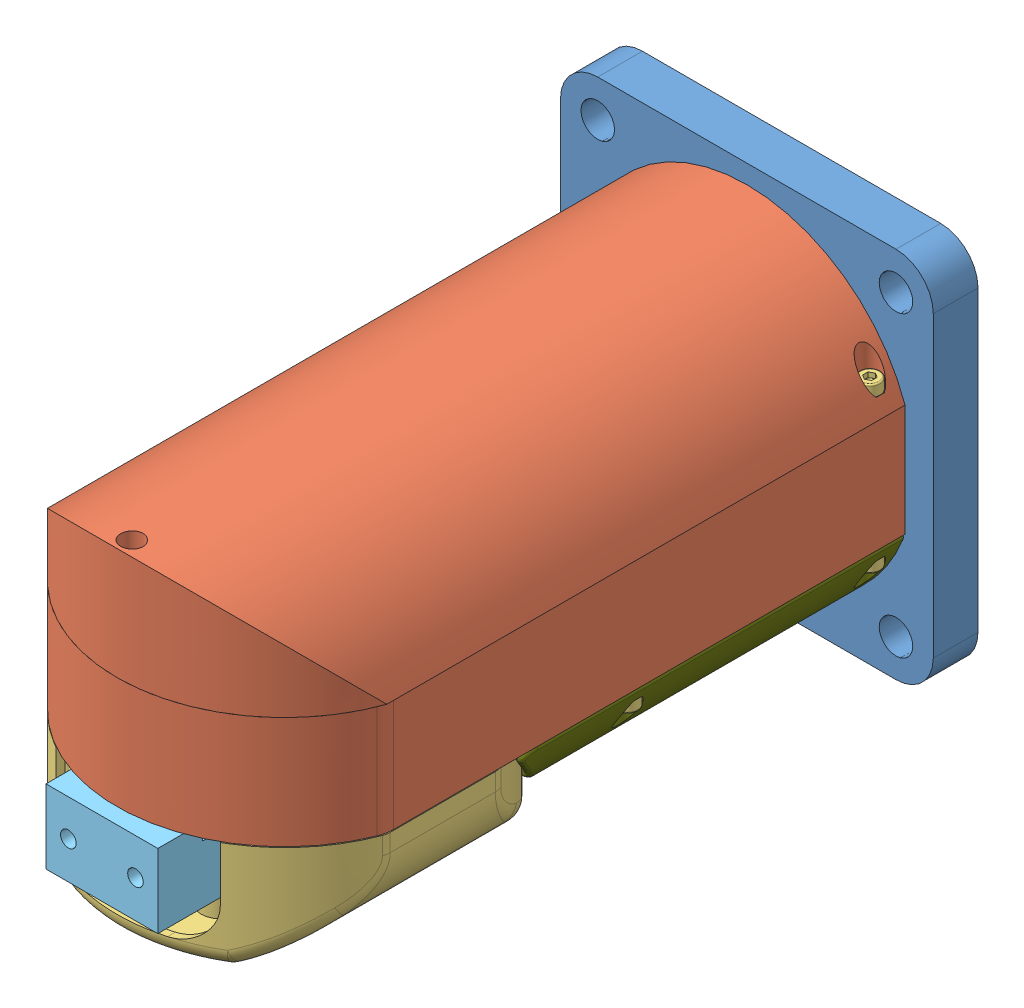
SolidWorks assembly 基座, configuration 默认. Lengths in mm.
Overall size (118.25 100 217.02).
86 component instances, 23 part files, 119 mates.
Components (placement in the parent):
- 90000001-底座安装板-1: 90000001-底座安装板 [默认] at origin size (100 100 12)
- 90000002-底座中间部件-1: 90000002-底座中间部件 [默认] at (0 0 -40) size (118.25 75 217.02)
- hexagon socket head cap screws gb-2: hexagon socket head cap screws gb [GB_FASTENER_SCREWS_HSHCS M6X20-N] at (37.5 0 -11.5) x (0 0 1) z (-1 0 0) size (26 10 10)
- hexagon socket head cap screws gb-3: hexagon socket head cap screws gb [GB_FASTENER_SCREWS_HSHCS M6X20-N] at (-37.5 0 -11.5) x (0 0 1) z (-1 0 0) size (26 10 10)
- 90000013-SHF-17-80-2SH-SP刚柔轮组件-1: 90000013-SHF-17-80-2SH-SP刚柔轮组件 [默认] at (0 7 124) x (0 0 -1) z (0 -1 0) size (80 80 29.5)
- 90000006-J1轴转接法兰-1: 90000006-J1轴转接法兰 [默认] at (0 0 79) x (-1 0 0) z (0 0 1) size (64 19.8 81.67)
- hexagon socket head cap screws gb-4: hexagon socket head cap screws gb [GB_FASTENER_SCREWS_HSHCS M3X25-N] at (18.5 -15 156.0429) x (0 1 0) z (0 0 1) size (28 5.5 5.5)
- hexagon socket head cap screws gb-5: hexagon socket head cap screws gb [GB_FASTENER_SCREWS_HSHCS M3X25-N] at (0 -15 161) x (0 1 0) z (-0.5 0 0.866025) size (28 5.5 5.5)
- hexagon socket head cap screws gb-6: hexagon socket head cap screws gb [GB_FASTENER_SCREWS_HSHCS M3X25-N] at (-18.5 -15 156.0429) x (0 1 0) z (-0.866025 0 0.5) size (28 5.5 5.5)
- hexagon socket head cap screws gb-7: hexagon socket head cap screws gb [GB_FASTENER_SCREWS_HSHCS M3X25-N] at (-32.0429 -15 142.5) x (0 1 0) z (-1 0 0) size (28 5.5 5.5)
- hexagon socket head cap screws gb-8: hexagon socket head cap screws gb [GB_FASTENER_SCREWS_HSHCS M3X25-N] at (-37 -15 124) x (0 1 0) z (-0.866025 0 -0.5) size (28 5.5 5.5)
- hexagon socket head cap screws gb-9: hexagon socket head cap screws gb [GB_FASTENER_SCREWS_HSHCS M3X25-N] at (-32.0429 -15 105.5) x (0 1 0) z (-0.5 0 -0.866025) size (28 5.5 5.5)
- hexagon socket head cap screws gb-10: hexagon socket head cap screws gb [GB_FASTENER_SCREWS_HSHCS M3X25-N] at (-18.5 -15 91.9571) x (0 1 0) z (0 0 -1) size (28 5.5 5.5)
- hexagon socket head cap screws gb-11: hexagon socket head cap screws gb [GB_FASTENER_SCREWS_HSHCS M3X25-N] at (0 -15 87) x (0 1 0) z (0.5 0 -0.866025) size (28 5.5 5.5)
- hexagon socket head cap screws gb-12: hexagon socket head cap screws gb [GB_FASTENER_SCREWS_HSHCS M3X25-N] at (18.5 -15 91.9571) x (0 1 0) z (0.866025 0 -0.5) size (28 5.5 5.5)
- hexagon socket head cap screws gb-13: hexagon socket head cap screws gb [GB_FASTENER_SCREWS_HSHCS M3X25-N] at (32.0429 -15 105.5) x (0 1 0) z (1 0 0) size (28 5.5 5.5)
- hexagon socket head cap screws gb-14: hexagon socket head cap screws gb [GB_FASTENER_SCREWS_HSHCS M3X25-N] at (37 -15 124) x (0 1 0) z (0.866025 0 0.5) size (28 5.5 5.5)
- hexagon socket head cap screws gb-15: hexagon socket head cap screws gb [GB_FASTENER_SCREWS_HSHCS M3X25-N] at (32.0429 -15 142.5) x (0 1 0) z (0.5 0 0.866025) size (28 5.5 5.5)
- 90000013-SHF-17-80-2SH-SP波发生器-1: 90000013-SHF-17-80-2SH-SP波发生器 [默认] at (0 -11.9 124) x (0.178391 0 0.98396) z (0 -1 0) size (45 45 7.6)
- 90000010-J1轴减速机安装法兰-1: 90000010-J1轴减速机安装法兰 [默认] at (0 16 124) x (1 0 0) z (0 -1 0) size (64 64 12.5)
- 90000009-J1轴减速机安装输出轴-1: 90000009-J1轴减速机安装输出轴 [默认] at (0 -30.5 124) x (0.178391 0 0.98396) z (0 1 0) size (27 27 62.5)
- hexagon socket head cap screws gb-16: hexagon socket head cap screws gb [GB_FASTENER_SCREWS_HSHCS M4X8-N] at (-1.9623 -5.9 113.1764) x (0 -1 0) z (0 0 1) size (12 7 7)
- hexagon socket head cap screws gb-17: hexagon socket head cap screws gb [GB_FASTENER_SCREWS_HSHCS M4X8-N] at (1.9623 -5.9 134.8236) x (0 -1 0) z (0 0 1) size (12 7 7)
- 90000012-轴承636-1: 90000012-轴承636 [默认] at (0 -31 124) x (-0.837169 0 -0.546944) z (0 1 0) size (22 22 9)
- hexagon socket head cap screws gb-18: hexagon socket head cap screws gb [GB_FASTENER_SCREWS_HSHCS M3X20-N] at (-15.8702 -30.5 102.1565) x (0 1 0) z (0 0 1) size (23 5.5 5.5)
- hexagon socket head cap screws gb-22: hexagon socket head cap screws gb [GB_FASTENER_SCREWS_HSHCS M3X20-N] at (-21.8435 -30.5 108.1298) x (0 1 0) z (0 0 1) size (23 5.5 5.5)
- hexagon socket head cap screws gb-26: hexagon socket head cap screws gb [GB_FASTENER_SCREWS_HSHCS M3X20-N] at (-25.6785 -30.5 115.6565) x (0 1 0) z (0 0 1) size (23 5.5 5.5)
- hexagon socket head cap screws gb-30: hexagon socket head cap screws gb [GB_FASTENER_SCREWS_HSHCS M3X20-N] at (-27 -30.5 124) x (0 1 0) z (0 0 1) size (23 5.5 5.5)
- hexagon socket head cap screws gb-19: hexagon socket head cap screws gb [GB_FASTENER_SCREWS_HSHCS M3X20-N] at (21.8435 -30.5 108.1298) x (0 1 0) z (-1 0 0) size (23 5.5 5.5)
- hexagon socket head cap screws gb-20: hexagon socket head cap screws gb [GB_FASTENER_SCREWS_HSHCS M3X20-N] at (15.8702 -30.5 145.8435) x (0 1 0) z (0 0 -1) size (23 5.5 5.5)
- hexagon socket head cap screws gb-21: hexagon socket head cap screws gb [GB_FASTENER_SCREWS_HSHCS M3X20-N] at (-21.8435 -30.5 139.8702) x (0 1 0) z (1 0 0) size (23 5.5 5.5)
- hexagon socket head cap screws gb-23: hexagon socket head cap screws gb [GB_FASTENER_SCREWS_HSHCS M3X20-N] at (15.8702 -30.5 102.1565) x (0 1 0) z (-1 0 0) size (23 5.5 5.5)
- hexagon socket head cap screws gb-24: hexagon socket head cap screws gb [GB_FASTENER_SCREWS_HSHCS M3X20-N] at (21.8435 -30.5 139.8702) x (0 1 0) z (0 0 -1) size (23 5.5 5.5)
- hexagon socket head cap screws gb-25: hexagon socket head cap screws gb [GB_FASTENER_SCREWS_HSHCS M3X20-N] at (-15.8702 -30.5 145.8435) x (0 1 0) z (1 0 0) size (23 5.5 5.5)
- hexagon socket head cap screws gb-27: hexagon socket head cap screws gb [GB_FASTENER_SCREWS_HSHCS M3X20-N] at (8.3435 -30.5 98.3215) x (0 1 0) z (-1 0 0) size (23 5.5 5.5)
- hexagon socket head cap screws gb-28: hexagon socket head cap screws gb [GB_FASTENER_SCREWS_HSHCS M3X20-N] at (25.6785 -30.5 132.3435) x (0 1 0) z (0 0 -1) size (23 5.5 5.5)
- hexagon socket head cap screws gb-29: hexagon socket head cap screws gb [GB_FASTENER_SCREWS_HSHCS M3X20-N] at (-8.3435 -30.5 149.6785) x (0 1 0) z (1 0 0) size (23 5.5 5.5)
- hexagon socket head cap screws gb-31: hexagon socket head cap screws gb [GB_FASTENER_SCREWS_HSHCS M3X20-N] at (0 -30.5 97) x (0 1 0) z (-1 0 0) size (23 5.5 5.5)
- hexagon socket head cap screws gb-32: hexagon socket head cap screws gb [GB_FASTENER_SCREWS_HSHCS M3X20-N] at (27 -30.5 124) x (0 1 0) z (0 0 -1) size (23 5.5 5.5)
- hexagon socket head cap screws gb-33: hexagon socket head cap screws gb [GB_FASTENER_SCREWS_HSHCS M3X20-N] at (0 -30.5 151) x (0 1 0) z (1 0 0) size (23 5.5 5.5)
- 90000011-轴承638-1: 90000011-轴承638 [默认] at (0 8 124) x (1 0 0) z (0 -1 0) size (28 28 9)
- hexagon socket head cap screws gb-34: hexagon socket head cap screws gb [GB_FASTENER_SCREWS_HSHCS M3X8-N] at (0 19 153) x (0 -1 0) z (-0.62239 0 0.782707) size (11 5.5 5.5)
- hexagon socket head cap screws gb-35: hexagon socket head cap screws gb [GB_FASTENER_SCREWS_HSHCS M3X8-N] at (-20.5061 19 144.5061) x (0 -1 0) z (-0.993554 0 0.113361) size (11 5.5 5.5)
- hexagon socket head cap screws gb-36: hexagon socket head cap screws gb [GB_FASTENER_SCREWS_HSHCS M3X8-N] at (-29 19 124) x (0 -1 0) z (-0.782707 0 -0.62239) size (11 5.5 5.5)
- hexagon socket head cap screws gb-37: hexagon socket head cap screws gb [GB_FASTENER_SCREWS_HSHCS M3X8-N] at (-20.5061 19 103.4939) x (0 -1 0) z (-0.113361 0 -0.993554) size (11 5.5 5.5)
- hexagon socket head cap screws gb-38: hexagon socket head cap screws gb [GB_FASTENER_SCREWS_HSHCS M3X8-N] at (0 19 95) x (0 -1 0) z (0.62239 0 -0.782707) size (11 5.5 5.5)
- hexagon socket head cap screws gb-39: hexagon socket head cap screws gb [GB_FASTENER_SCREWS_HSHCS M3X8-N] at (20.5061 19 103.4939) x (0 -1 0) z (0.993554 0 -0.113361) size (11 5.5 5.5)
- hexagon socket head cap screws gb-40: hexagon socket head cap screws gb [GB_FASTENER_SCREWS_HSHCS M3X8-N] at (29 19 124) x (0 -1 0) z (0.782707 0 0.62239) size (11 5.5 5.5)
- hexagon socket head cap screws gb-41: hexagon socket head cap screws gb [GB_FASTENER_SCREWS_HSHCS M3X8-N] at (20.5061 19 144.5061) x (0 -1 0) z (0.113361 0 0.993554) size (11 5.5 5.5)
- 90000022-NOK油封AE0090A0-1: 90000022-NOK油封AE0090A0 [默认] at (0 16 124) x (1 0 0) z (0 -1 0) size (20 20 7)
- 90000005-J1轴电机安装板-1: 90000005-J1轴电机安装板 [默认] at (0 9.2 52) x (1 0 0) z (0 -1 0) size (70 42 2.2)
- hexagon socket head cap screws gb-42: hexagon socket head cap screws gb [GB_FASTENER_SCREWS_HSHCS M3X8-N] at (32 12.2 67.5) x (0 -1 0) z (0 0 1) size (11 5.5 5.5)
- hexagon socket head cap screws gb-43: hexagon socket head cap screws gb [GB_FASTENER_SCREWS_HSHCS M3X8-N] at (-32 12.2 67.5) x (0 -1 0) z (0 0 1) size (11 5.5 5.5)
- hexagon socket head cap screws gb-44: hexagon socket head cap screws gb [GB_FASTENER_SCREWS_HSHCS M3X8-N] at (32 12.2 36.5) x (0 -1 0) z (0 0 1) size (11 5.5 5.5)
- hexagon socket head cap screws gb-45: hexagon socket head cap screws gb [GB_FASTENER_SCREWS_HSHCS M3X8-N] at (-32 12.2 36.5) x (0 -1 0) z (0 0 1) size (11 5.5 5.5)
- 90000015-汉德宝1701HS06AX-1: 90000015-汉德宝1701HS06AX [默认] at (0 -24 52) x (1 0 0) z (0 1 0) size (42.3 42.3 55)
- hexagon socket head cap screws gb-46: hexagon socket head cap screws gb [GB_FASTENER_SCREWS_HSHCS M3X8-N] at (15.5 12.2 67.5) x (0 -1 0) z (0 0 1) size (11 5.5 5.5)
- hexagon socket head cap screws gb-47: hexagon socket head cap screws gb [GB_FASTENER_SCREWS_HSHCS M3X8-N] at (-15.5 12.2 67.5) x (0 -1 0) z (0 0 1) size (11 5.5 5.5)
- hexagon socket head cap screws gb-48: hexagon socket head cap screws gb [GB_FASTENER_SCREWS_HSHCS M3X8-N] at (-15.5 12.2 36.5) x (0 -1 0) z (0 0 1) size (11 5.5 5.5)
- hexagon socket head cap screws gb-49: hexagon socket head cap screws gb [GB_FASTENER_SCREWS_HSHCS M3X8-N] at (15.5 12.2 36.5) x (0 -1 0) z (0 0 1) size (11 5.5 5.5)
- 90000007-3GT-24齿-6同步带轮-1: 90000007-3GT-24齿-6同步带轮 [默认] at (0 25.4 52) x (-0.049982 0 -0.99875) z (0 1 0) size (29.8 29.8 8)
- 90000014-BXR-020-10E抱闸-1: 90000014-BXR-020-10E抱闸 [默认] at (0 9.2 52) x (0.866025 0 -0.5) z (0 1 0) size (32 32 14)
- 90000003-底座中间部件左端盖-1: 90000003-底座中间部件左端盖 [默认] x (-1 0 0) z (0 0 1) size (84.36 33.92 105.12)
- 90000008-3GT-24齿-6减速机端同步带轮-1: 90000008-3GT-24齿-6减速机端同步带轮 [默认] at (0 23 124) x (0.98396 0 -0.178391) z (0 1 0) size (35.8 35.8 14)
- 90000023-240-3GT-6-1: 90000023-240-3GT-6 [默认] at (0 30.4 124) x (0 0 -1) z (0 -1 0) size (104.36 32.36 6)
- hex socket set screws with flat point gb-4: hex socket set screws with flat point gb [GB_FASTENER_SCREWS_HSFP M4X5-N] at (-1.3379 27.5 116.6203) x (0.178391 0 0.98396) z (-0.604831 0.788768 0.109655) size (5 4 4)
- hex socket set screws with flat point gb-5: hex socket set screws with flat point gb [GB_FASTENER_SCREWS_HSFP M4X5-N] at (7.3797 27.5 122.6621) x (-0.98396 0 0.178391) z (-0.109655 0.788768 -0.604831) size (5 4 4)
- 90000004-底座中间部件右端盖-1: 90000004-底座中间部件右端盖 [默认] at (0 0 169) x (-1 0 0) z (0 0 -1) size (84.85 31.21 169)
- hexagon socket head cap screws gb-50: hexagon socket head cap screws gb [GB_FASTENER_SCREWS_HSHCS M3X8-N] at (38 22 5) x (0 -1 0) z (0 0 1) size (11 5.5 5.5)
- hexagon socket head cap screws gb-51: hexagon socket head cap screws gb [GB_FASTENER_SCREWS_HSHCS M3X8-N] at (-38 22 5) x (0 -1 0) z (0 0 1) size (11 5.5 5.5)
- hexagon socket head cap screws gb-52: hexagon socket head cap screws gb [GB_FASTENER_SCREWS_HSHCS M3X8-N] at (0 22 165) x (0 -1 0) z (0 0 1) size (11 5.5 5.5)
- hexagon socket head cap screws gb-53: hexagon socket head cap screws gb [GB_FASTENER_SCREWS_HSHCS M3X8-N] at (38 -22 70) x (0 1 0) z (0.546944 0 -0.837169) size (11 5.5 5.5)
- hexagon socket head cap screws gb-54: hexagon socket head cap screws gb [GB_FASTENER_SCREWS_HSHCS M3X8-N] at (38 -22 5) x (0 1 0) z (0.546944 0 -0.837169) size (11 5.5 5.5)
- hexagon socket head cap screws gb-55: hexagon socket head cap screws gb [GB_FASTENER_SCREWS_HSHCS M3X8-N] at (-38 -22 5) x (0 1 0) z (0.546944 0 -0.837169) size (11 5.5 5.5)
- hexagon socket head cap screws gb-56: hexagon socket head cap screws gb [GB_FASTENER_SCREWS_HSHCS M3X8-N] at (-38 -22 70) x (0 1 0) z (0.546944 0 -0.837169) size (11 5.5 5.5)
- hex socket set screws with flat point gb-6: hex socket set screws with flat point gb [GB_FASTENER_SCREWS_HSFP M4X5-N] at (-0.5722 27.4 40.566) x (0.049982 0 0.99875) z (-0.99875 0 0.049982) size (5 4 4)
- 90000024-底座法兰端盖-1: 90000024-底座法兰端盖 [默认] at (0 0 79) x (-1 0 0) z (0 0 1) size (86.96 29.8 90) (hidden)
- hexagon socket head cap screws gb-57: hexagon socket head cap screws gb [GB_FASTENER_SCREWS_HSHCS M3X8-N] at (8.3435 -42 149.6785) x (0 1 0) z (0.999688 0 -0.024966) size (11 5.5 5.5)
- hexagon socket head cap screws gb-58: hexagon socket head cap screws gb [GB_FASTENER_SCREWS_HSHCS M3X8-N] at (25.6785 -42 115.6565) x (0 1 0) z (-0.024966 0 -0.999688) size (11 5.5 5.5)
- hexagon socket head cap screws gb-59: hexagon socket head cap screws gb [GB_FASTENER_SCREWS_HSHCS M3X8-N] at (-8.3435 -42 98.3215) x (0 1 0) z (-0.999688 0 0.024966) size (11 5.5 5.5)
- hexagon socket head cap screws gb-60: hexagon socket head cap screws gb [GB_FASTENER_SCREWS_HSHCS M3X8-N] at (-25.6785 -42 132.3435) x (0 1 0) z (0.024966 0 0.999688) size (11 5.5 5.5)
- 90000025-PCBboard安装柱-1: 90000025-PCBboard安装柱 [默认] at (25 0 10.5) x (-0.923728 -0.383049 0) z (0 0 -1) size (5 6 10)
- 90000025-PCBboard安装柱-2: 90000025-PCBboard安装柱 [默认] at (-25 0 10.5) x (-0.923728 -0.383049 0) z (0 0 -1) size (5 6 10)
- 90000026-PCBboard-1: 90000026-PCBboard [默认] at (0 0 10.5) size (65 70 5)
- hexagon socket head cap screws gb-61: hexagon socket head cap screws gb [GB_FASTENER_SCREWS_HSHCS M3X8-N] at (25 0 18.5) x (0 0 -1) z (0.825904 -0.56381 0) size (11 5.5 5.5)
- hexagon socket head cap screws gb-62: hexagon socket head cap screws gb [GB_FASTENER_SCREWS_HSHCS M3X8-N] at (-25 0 18.5) x (0 0 -1) z (0.825904 -0.56381 0) size (11 5.5 5.5)
Mates (geometry in assembly coordinates):
- 重合1: coincident aligned: plane of 90000001-底座安装板-1 through (0 0 0) normal (0 0 1); plane of assembly through (0 0 0) normal (0 0 1)
- 重合2: coincident aligned: plane of 90000001-底座安装板-1 through (0 0 0) normal (0 1 0); plane of assembly through (0 0 0) normal (0 1 0)
- 重合3: coincident aligned: plane of 90000001-底座安装板-1 through (0 0 0) normal (1 0 0); plane of assembly through (0 0 0) normal (1 0 0)
- 同心1: concentric aligned: cylinder of 90000001-底座安装板-1 through (-37.5 0 -5.5) axis (0 0 -1) radius 5.5; cylinder of 90000002-底座中间部件-1 through (-37.5 0 0) axis (0 0 -1) radius 2.5
- 同心2: concentric aligned: cylinder of 90000001-底座安装板-1 through (37.5 0 199) axis (0 0 -1) radius 3.3; cylinder of 90000002-底座中间部件-1 through (37.5 0 0) axis (0 0 -1) radius 2.5
- 重合4: coincident anti-aligned: plane of 90000001-底座安装板-1 through (0 0 0) normal (0 0 1); plane of 90000002-底座中间部件-1 through (0 0 0) normal (0 0 -1)
- 同心3: concentric aligned: cylinder of 90000001-底座安装板-1 through (37.5 0 -5.5) axis (0 0 -1) radius 5.5; cylinder of hexagon socket head cap screws gb-2 through (37.5 0 14.5) axis (0 0 -1) radius 3
- 重合5: coincident anti-aligned: plane of 90000001-底座安装板-1 through (37.5 0 -5.5) normal (0 0 -1); plane of hexagon socket head cap screws gb-2 through (37.5 0 -5.5) normal (0 0 1)
- 同心4: concentric aligned: cylinder of 90000001-底座安装板-1 through (-37.5 0 199) axis (0 0 -1) radius 3.3; cylinder of hexagon socket head cap screws gb-3 through (-37.5 0 14.5) axis (0 0 -1) radius 3
- 重合6: coincident anti-aligned: plane of 90000001-底座安装板-1 through (-37.5 0 -5.5) normal (0 0 -1); plane of hexagon socket head cap screws gb-3 through (-37.5 0 -5.5) normal (0 0 1)
- 同心6: concentric aligned: cylinder of 90000002-底座中间部件-1 through (0 29 124) axis (0 -1 0) radius 23; cylinder of 90000013-SHF-17-80-2SH-SP刚柔轮组件-1 through (0 -12 124) axis (0 -1 0) radius 30
- 同心7: concentric aligned: cylinder of 90000002-底座中间部件-1 through (-26.163 10.5 97.837) axis (0 -1 0) radius 3; cylinder of 90000013-SHF-17-80-2SH-SP刚柔轮组件-1 through (-26.163 10 97.837) axis (0 -1 0) radius 2.75
- 重合7: coincident anti-aligned: plane of 90000002-底座中间部件-1 through (0 7 124) normal (0 -1 0); plane of 90000013-SHF-17-80-2SH-SP刚柔轮组件-1 through (0 7 124) normal (0 1 0)
- 同心8: concentric aligned: cylinder of 90000013-SHF-17-80-2SH-SP刚柔轮组件-1 through (18.5 47.5 156.0429) axis (0 -1 0) radius 1.75; cylinder of hexagon socket head cap screws gb-4 through (18.5 13 156.0429) axis (0 -1 0) radius 1.5
- 重合8: coincident anti-aligned: plane of 90000013-SHF-17-80-2SH-SP刚柔轮组件-1 through (0 -12 124) normal (0 -1 0); plane of hexagon socket head cap screws gb-4 through (18.5 -12 156.0429) normal (0 1 0)
- 同心9: concentric anti-aligned: cylinder of 90000013-SHF-17-80-2SH-SP刚柔轮组件-1 through (0 40 124) axis (0 -1 0) radius 22.5; cylinder of 90000013-SHF-17-80-2SH-SP波发生器-1 through (0 -19.5 124) axis (0 1 0) radius 22.5
- 重合9: coincident aligned: plane of 90000013-SHF-17-80-2SH-SP刚柔轮组件-1 through (0 -19.5 124) normal (0 -1 0); plane of 90000013-SHF-17-80-2SH-SP波发生器-1 through (0 -19.5 124) normal (0 -1 0)
- 同心10: concentric anti-aligned: cylinder of 90000013-SHF-17-80-2SH-SP波发生器-1 through (0 -19.5 124) axis (0 1 0) radius 4; cylinder of 90000009-J1轴减速机安装输出轴-1 through (0 20.5 124) axis (0 -1 0) radius 4
- 同心11: concentric aligned: cylinder of 90000013-SHF-17-80-2SH-SP波发生器-1 through (1.9623 -19.5 134.8236) axis (0 -1 0) radius 1.65; cylinder of 90000009-J1轴减速机安装输出轴-1 through (1.9623 -9.9 134.8236) axis (0 -1 0) radius 2.25
- 重合10: coincident anti-aligned: plane of 90000013-SHF-17-80-2SH-SP波发生器-1 through (0 -11.9 124) normal (0 1 0); plane of 90000009-J1轴减速机安装输出轴-1 through (0 -11.9 124) normal (0 -1 0)
- 同心12: concentric anti-aligned: cylinder of 90000013-SHF-17-80-2SH-SP波发生器-1 through (-1.9623 -19.5 113.1764) axis (0 -1 0) radius 1.65; cylinder of hexagon socket head cap screws gb-16 through (-1.9623 -17.9 113.1764) axis (0 1 0) radius 2
- 重合11: coincident anti-aligned: plane of 90000009-J1轴减速机安装输出轴-1 through (0 -9.9 124) normal (0 1 0); plane of hexagon socket head cap screws gb-16 through (-1.9623 -9.9 113.1764) normal (0 -1 0)
- 同心13: concentric anti-aligned: cylinder of 90000013-SHF-17-80-2SH-SP波发生器-1 through (1.9623 -19.5 134.8236) axis (0 -1 0) radius 1.65; cylinder of hexagon socket head cap screws gb-17 through (1.9623 -17.9 134.8236) axis (0 1 0) radius 2
- 重合12: coincident anti-aligned: plane of 90000009-J1轴减速机安装输出轴-1 through (0 -9.9 124) normal (0 1 0); plane of hexagon socket head cap screws gb-17 through (1.9623 -9.9 134.8236) normal (0 -1 0)
- 同心14: concentric anti-aligned: cylinder of 90000006-J1轴转接法兰-1 through (0 -31.5 124) axis (0 1 0) radius 11; cylinder of 90000012-轴承636-1 through (0 -22 124) axis (0 -1 0) radius 11
- 重合13: coincident anti-aligned: plane of 90000006-J1轴转接法兰-1 through (0 -31 124) normal (0 1 0); plane of 90000012-轴承636-1 through (0 -31 124) normal (0 -1 0)
- 同心15: concentric aligned: cylinder of 90000009-J1轴减速机安装输出轴-1 through (0 -22 124) axis (0 -1 0) radius 3; cylinder of 90000012-轴承636-1 through (0 -22 124) axis (0 -1 0) radius 3
- 同心16: concentric aligned: cylinder of 90000013-SHF-17-80-2SH-SP刚柔轮组件-1 through (0 -19.5 151) axis (0 -1 0) radius 1.25; cylinder of 90000006-J1轴转接法兰-1 through (0 -27.5 151) axis (0 -1 0) radius 3
- 重合14: coincident anti-aligned: plane of 90000013-SHF-17-80-2SH-SP刚柔轮组件-1 through (0 -19.5 124) normal (0 -1 0); plane of 90000006-J1轴转接法兰-1 through (0 -19.5 124) normal (0 1 0)
- 同心17: concentric aligned: cylinder of 90000006-J1轴转接法兰-1 through (-15.8702 -27.5 102.1565) axis (0 -1 0) radius 3; cylinder of hexagon socket head cap screws gb-18 through (-15.8702 -7.5 102.1565) axis (0 -1 0) radius 1.5
- 重合15: coincident anti-aligned: plane of 90000006-J1轴转接法兰-1 through (-15.8702 -27.5 102.1565) normal (0 -1 0); plane of hexagon socket head cap screws gb-18 through (-15.8702 -27.5 102.1565) normal (0 1 0)
- 同心18: concentric aligned: cylinder of 90000006-J1轴转接法兰-1 through (-21.8435 15 108.1298) axis (0 -1 0) radius 1.7; cylinder of hexagon socket head cap screws gb-22 through (-21.8435 -7.5 108.1298) axis (0 -1 0) radius 1.5
- 重合16: coincident anti-aligned: plane of 90000006-J1轴转接法兰-1 through (-21.8435 -27.5 108.1298) normal (0 -1 0); plane of hexagon socket head cap screws gb-22 through (-21.8435 -27.5 108.1298) normal (0 1 0)
- 同心19: concentric aligned: cylinder of 90000006-J1轴转接法兰-1 through (-25.6785 15 115.6565) axis (0 -1 0) radius 1.7; cylinder of hexagon socket head cap screws gb-26 through (-25.6785 -7.5 115.6565) axis (0 -1 0) radius 1.5
- 重合17: coincident anti-aligned: plane of 90000006-J1轴转接法兰-1 through (-25.6785 -27.5 115.6565) normal (0 -1 0); plane of hexagon socket head cap screws gb-26 through (-25.6785 -27.5 115.6565) normal (0 1 0)
- 同心20: concentric aligned: cylinder of 90000006-J1轴转接法兰-1 through (-27 15 124) axis (0 -1 0) radius 1.7; cylinder of hexagon socket head cap screws gb-30 through (-27 -7.5 124) axis (0 -1 0) radius 1.5
- 重合18: coincident anti-aligned: plane of 90000006-J1轴转接法兰-1 through (-27 -27.5 124) normal (0 -1 0); plane of hexagon socket head cap screws gb-30 through (-27 -27.5 124) normal (0 1 0)
- 同心21: concentric aligned: cylinder of 90000002-底座中间部件-1 through (0 11.5 124) axis (0 1 0) radius 32.5; cylinder of 90000010-J1轴减速机安装法兰-1 through (0 3.5 124) axis (0 1 0) radius 18
- 同心22: concentric anti-aligned: cylinder of 90000002-底座中间部件-1 through (0 11.5 153) axis (0 1 0) radius 1.25; cylinder of 90000010-J1轴减速机安装法兰-1 through (0 21.5 153) axis (0 -1 0) radius 1.7
- 重合19: coincident anti-aligned: plane of 90000002-底座中间部件-1 through (0 11.5 124) normal (0 1 0); plane of 90000010-J1轴减速机安装法兰-1 through (0 11.5 124) normal (0 -1 0)
- 同心23: concentric anti-aligned: cylinder of 90000009-J1轴减速机安装输出轴-1 through (0 20.5 124) axis (0 -1 0) radius 4; cylinder of 90000011-轴承638-1 through (0 -1 124) axis (0 1 0) radius 4
- 重合20: coincident anti-aligned: plane of 90000009-J1轴减速机安装输出轴-1 through (0 -1 124) normal (0 1 0); plane of 90000011-轴承638-1 through (0 -1 124) normal (0 -1 0)
- 同心24: concentric anti-aligned: cylinder of 90000010-J1轴减速机安装法兰-1 through (0 21.5 153) axis (0 -1 0) radius 1.7; cylinder of hexagon socket head cap screws gb-34 through (0 8 153) axis (0 1 0) radius 1.5
- 重合21: coincident anti-aligned: plane of 90000010-J1轴减速机安装法兰-1 through (0 16 124) normal (0 1 0); plane of hexagon socket head cap screws gb-34 through (0 16 153) normal (0 -1 0)
- 同心25: concentric anti-aligned: cylinder of 90000010-J1轴减速机安装法兰-1 through (0 9 124) axis (0 1 0) radius 10; cylinder of 90000022-NOK油封AE0090A0-1 through (0 13 124) axis (0 -1 0) radius 9
- 重合22: coincident aligned: plane of 90000010-J1轴减速机安装法兰-1 through (0 16 124) normal (0 1 0); plane of 90000022-NOK油封AE0090A0-1 through (0 16 124) normal (0 1 0)
- 同心26: concentric aligned: cylinder of 90000002-底座中间部件-1 through (-32 15 67.5) axis (0 1 0) radius 1.25; cylinder of 90000005-J1轴电机安装板-1 through (-32 7 67.5) axis (0 1 0) radius 1.75
- 同心27: concentric aligned: cylinder of 90000002-底座中间部件-1 through (-32 15 36.5) axis (0 1 0) radius 1.25; cylinder of 90000005-J1轴电机安装板-1 through (-32 7 36.5) axis (0 1 0) radius 1.75
- 重合23: coincident anti-aligned: plane of 90000002-底座中间部件-1 through (0 7 -40) normal (0 1 0); plane of 90000005-J1轴电机安装板-1 through (0 7 52) normal (0 -1 0)
- 同心28: concentric aligned: cylinder of 90000005-J1轴电机安装板-1 through (32 7 67.5) axis (0 1 0) radius 1.75; cylinder of hexagon socket head cap screws gb-42 through (32 1.2 67.5) axis (0 1 0) radius 1.5
- 重合24: coincident anti-aligned: plane of 90000005-J1轴电机安装板-1 through (0 9.2 52) normal (0 1 0); plane of hexagon socket head cap screws gb-42 through (32 9.2 67.5) normal (0 -1 0)
- 同心29: concentric aligned: cylinder of 90000005-J1轴电机安装板-1 through (-32 7 67.5) axis (0 1 0) radius 1.75; cylinder of hexagon socket head cap screws gb-43 through (-32 1.2 67.5) axis (0 1 0) radius 1.5
- 重合25: coincident anti-aligned: plane of 90000005-J1轴电机安装板-1 through (0 9.2 52) normal (0 1 0); plane of hexagon socket head cap screws gb-43 through (-32 9.2 67.5) normal (0 -1 0)
- 同心30: concentric aligned: cylinder of 90000005-J1轴电机安装板-1 through (32 7 36.5) axis (0 1 0) radius 1.75; cylinder of hexagon socket head cap screws gb-44 through (32 1.2 36.5) axis (0 1 0) radius 1.5
- 重合26: coincident anti-aligned: plane of 90000005-J1轴电机安装板-1 through (0 9.2 52) normal (0 1 0); plane of hexagon socket head cap screws gb-44 through (32 9.2 36.5) normal (0 -1 0)
- 同心31: concentric aligned: cylinder of 90000005-J1轴电机安装板-1 through (-32 7 36.5) axis (0 1 0) radius 1.75; cylinder of hexagon socket head cap screws gb-45 through (-32 1.2 36.5) axis (0 1 0) radius 1.5
- 重合27: coincident anti-aligned: plane of 90000005-J1轴电机安装板-1 through (0 9.2 52) normal (0 1 0); plane of hexagon socket head cap screws gb-45 through (-32 9.2 36.5) normal (0 -1 0)
- 同心32: concentric anti-aligned: cylinder of 90000005-J1轴电机安装板-1 through (0 7 52) axis (0 1 0) radius 11.5; cylinder of 90000015-汉德宝1701HS06AX-1 through (0 31 52) axis (0 -1 0) radius 2.5
- 同心33: concentric anti-aligned: cylinder of 90000005-J1轴电机安装板-1 through (-15.5 17 67.5) axis (0 -1 0) radius 1.75; cylinder of 90000015-汉德宝1701HS06AX-1 through (-15.5 7 67.5) axis (0 1 0) radius 1.25
- 重合28: coincident anti-aligned: plane of 90000005-J1轴电机安装板-1 through (0 7 52) normal (0 -1 0); plane of 90000015-汉德宝1701HS06AX-1 through (0 7 52) normal (0 1 0)
- 同心34: concentric aligned: cylinder of 90000015-汉德宝1701HS06AX-1 through (15.5 7 67.5) axis (0 1 0) radius 1.25; cylinder of hexagon socket head cap screws gb-46 through (15.5 1.2 67.5) axis (0 1 0) radius 1.5
- 重合29: coincident anti-aligned: plane of 90000005-J1轴电机安装板-1 through (0 9.2 52) normal (0 1 0); plane of hexagon socket head cap screws gb-46 through (15.5 9.2 67.5) normal (0 -1 0)
- 同心35: concentric aligned: cylinder of 90000015-汉德宝1701HS06AX-1 through (-15.5 7 67.5) axis (0 1 0) radius 1.25; cylinder of hexagon socket head cap screws gb-47 through (-15.5 1.2 67.5) axis (0 1 0) radius 1.5
- 重合30: coincident anti-aligned: plane of 90000005-J1轴电机安装板-1 through (0 9.2 52) normal (0 1 0); plane of hexagon socket head cap screws gb-47 through (-15.5 9.2 67.5) normal (0 -1 0)
- 同心36: concentric aligned: cylinder of 90000015-汉德宝1701HS06AX-1 through (-15.5 7 36.5) axis (0 1 0) radius 1.25; cylinder of hexagon socket head cap screws gb-48 through (-15.5 1.2 36.5) axis (0 1 0) radius 1.5
- 重合31: coincident anti-aligned: plane of 90000005-J1轴电机安装板-1 through (0 9.2 52) normal (0 1 0); plane of hexagon socket head cap screws gb-48 through (-15.5 9.2 36.5) normal (0 -1 0)
- 同心37: concentric aligned: cylinder of 90000015-汉德宝1701HS06AX-1 through (15.5 7 36.5) axis (0 1 0) radius 1.25; cylinder of hexagon socket head cap screws gb-49 through (15.5 1.2 36.5) axis (0 1 0) radius 1.5
- 重合32: coincident anti-aligned: plane of 90000005-J1轴电机安装板-1 through (0 9.2 52) normal (0 1 0); plane of hexagon socket head cap screws gb-49 through (15.5 9.2 36.5) normal (0 -1 0)
- 同心44: concentric anti-aligned: cylinder of 90000002-底座中间部件-1 through (-38 -15 5) axis (0 -1 0) radius 1.25; cylinder of 90000003-底座中间部件左端盖-1 through (-38 -515 5) axis (0 1 0) radius 1.7
- 同心45: concentric anti-aligned: cylinder of 90000002-底座中间部件-1 through (38 -15 5) axis (0 -1 0) radius 1.25; cylinder of 90000003-底座中间部件左端盖-1 through (38 -515 5) axis (0 1 0) radius 1.7
- 重合38: coincident anti-aligned: plane of 90000002-底座中间部件-1 through (-100 -15 175.4185) normal (0 -1 0); plane of 90000003-底座中间部件左端盖-1 through (0 -15 0) normal (0 1 0)
- 同心46: concentric anti-aligned: cylinder of 90000009-J1轴减速机安装输出轴-1 through (0 18 124) axis (0 1 0) radius 3; cylinder of 90000008-3GT-24齿-6减速机端同步带轮-1 through (0 34 124) axis (0 -1 0) radius 3
- 同心47: concentric anti-aligned: cylinder of 90000008-3GT-24齿-6减速机端同步带轮-1 through (0 32 124) axis (0 -1 0) radius 14.9; cylinder of 90000023-240-3GT-6-1 through (0 24.4 124) axis (0 1 0) radius 14.9
- 重合41: coincident aligned: plane of 90000009-J1轴减速机安装输出轴-1 through (0 32 124) normal (0 1 0); plane of 90000008-3GT-24齿-6减速机端同步带轮-1 through (0 32 124) normal (0 1 0)
- 同心50: concentric aligned: cylinder of 90000008-3GT-24齿-6减速机端同步带轮-1 through (-2.6759 27.5 109.2406) axis (-0.178391 0 -0.98396) radius 1.65; cylinder of hex socket set screws with flat point gb-4 through (-3.2547 27.5 106.0476) axis (-0.178391 0 -0.98396) radius 2
- 重合42: coincident anti-aligned: plane of 90000009-J1轴减速机安装输出轴-1 through (-5.3658 19 122.4321) normal (-0.178391 0 -0.98396); plane of hex socket set screws with flat point gb-4 through (-0.446 27.5 121.5401) normal (0.178391 0 0.98396)
- 同心51: concentric aligned: cylinder of 90000008-3GT-24齿-6减速机端同步带轮-1 through (14.7594 27.5 121.3241) axis (0.98396 0 -0.178391) radius 1.65; cylinder of hex socket set screws with flat point gb-5 through (17.9524 27.5 120.7453) axis (0.98396 0 -0.178391) radius 2
- 重合44: coincident anti-aligned: plane of 90000009-J1轴减速机安装输出轴-1 through (1.5679 19 118.6342) normal (0.98396 0 -0.178391); plane of hex socket set screws with flat point gb-5 through (2.4599 27.5 123.554) normal (-0.98396 0 0.178391)
- 同心52: concentric aligned: cylinder of 90000002-底座中间部件-1 through (-38 15 5) axis (0 1 0) radius 1.25; cylinder of 90000004-底座中间部件右端盖-1 through (-38 0 5) axis (0 1 0) radius 1.7
- 同心53: concentric aligned: cylinder of 90000002-底座中间部件-1 through (38 15 5) axis (0 1 0) radius 1.25; cylinder of 90000004-底座中间部件右端盖-1 through (38 0 5) axis (0 1 0) radius 1.7
- 重合45: coincident anti-aligned: plane of 90000002-底座中间部件-1 through (-100 15 175.4185) normal (0 1 0); plane of 90000004-底座中间部件右端盖-1 through (0 15 169) normal (0 -1 0)
- 同心54: concentric aligned: cylinder of 90000004-底座中间部件右端盖-1 through (38 0 5) axis (0 1 0) radius 1.7; cylinder of hexagon socket head cap screws gb-50 through (38 11 5) axis (0 1 0) radius 1.5
- 重合46: coincident anti-aligned: plane of 90000004-底座中间部件右端盖-1 through (38 19 5) normal (0 1 0); plane of hexagon socket head cap screws gb-50 through (38 19 5) normal (0 -1 0)
- 同心55: concentric aligned: cylinder of 90000004-底座中间部件右端盖-1 through (-38 0 5) axis (0 1 0) radius 1.7; cylinder of hexagon socket head cap screws gb-51 through (-38 11 5) axis (0 1 0) radius 1.5
- 重合47: coincident anti-aligned: plane of 90000004-底座中间部件右端盖-1 through (-38 19 5) normal (0 1 0); plane of hexagon socket head cap screws gb-51 through (-38 19 5) normal (0 -1 0)
- 同心56: concentric aligned: cylinder of 90000004-底座中间部件右端盖-1 through (0 19 165) axis (0 1 0) radius 3; cylinder of hexagon socket head cap screws gb-52 through (0 11 165) axis (0 1 0) radius 1.5
- 重合48: coincident anti-aligned: plane of 90000004-底座中间部件右端盖-1 through (0 19 165) normal (0 1 0); plane of hexagon socket head cap screws gb-52 through (0 19 165) normal (0 -1 0)
- 同心57: concentric anti-aligned: cylinder of 90000003-底座中间部件左端盖-1 through (38 -515 70) axis (0 1 0) radius 1.7; cylinder of hexagon socket head cap screws gb-53 through (38 -11 70) axis (0 -1 0) radius 1.5
- 重合49: coincident anti-aligned: plane of 90000003-底座中间部件左端盖-1 through (0 -19 0) normal (0 -1 0); plane of hexagon socket head cap screws gb-53 through (38 -19 70) normal (0 1 0)
- 同心58: concentric anti-aligned: cylinder of 90000003-底座中间部件左端盖-1 through (38 -515 5) axis (0 1 0) radius 1.7; cylinder of hexagon socket head cap screws gb-54 through (38 -11 5) axis (0 -1 0) radius 1.5
- 重合50: coincident anti-aligned: plane of 90000003-底座中间部件左端盖-1 through (0 -19 0) normal (0 -1 0); plane of hexagon socket head cap screws gb-54 through (38 -19 5) normal (0 1 0)
- 同心59: concentric anti-aligned: cylinder of 90000003-底座中间部件左端盖-1 through (-38 -515 5) axis (0 1 0) radius 1.7; cylinder of hexagon socket head cap screws gb-55 through (-38 -11 5) axis (0 -1 0) radius 1.5
- 重合51: coincident anti-aligned: plane of 90000003-底座中间部件左端盖-1 through (0 -19 0) normal (0 -1 0); plane of hexagon socket head cap screws gb-55 through (-38 -19 5) normal (0 1 0)
- 同心60: concentric anti-aligned: cylinder of 90000003-底座中间部件左端盖-1 through (-38 -515 70) axis (0 1 0) radius 1.7; cylinder of hexagon socket head cap screws gb-56 through (-38 -11 70) axis (0 -1 0) radius 1.5
- 重合52: coincident anti-aligned: plane of 90000003-底座中间部件左端盖-1 through (0 -19 0) normal (0 -1 0); plane of hexagon socket head cap screws gb-56 through (-38 -19 70) normal (0 1 0)
- 同心61: concentric aligned: cylinder of 90000007-3GT-24齿-6同步带轮-1 through (-0.7497 27.4 37.0187) axis (-0.049982 0 -0.99875) radius 1.65; cylinder of hex socket set screws with flat point gb-6 through (-1.1093 27.4 29.8344) axis (-0.049982 0 -0.99875) radius 2
- 同心62: concentric anti-aligned: cylinder of 90000015-汉德宝1701HS06AX-1 through (0 31 52) axis (0 -1 0) radius 2.5; cylinder of 90000007-3GT-24齿-6同步带轮-1 through (0 31.4 52) axis (0 1 0) radius 2.5
- 距离1: distance = 1 mm aligned: plane of 90000007-3GT-24齿-6同步带轮-1 through (0 23.4 52) normal (0 -1 0); plane of 90000023-240-3GT-6-1 through (0 24.4 52) normal (0 -1 0)
- 距离2: distance = 0.2 mm anti-aligned: plane of 90000007-3GT-24齿-6同步带轮-1 through (0 23.4 52) normal (0 -1 0); plane of 90000014-BXR-020-10E抱闸-1 through (-5.9273 23.2 74.1177) normal (0 1 0)
- 同心63: concentric anti-aligned: cylinder of 90000015-汉德宝1701HS06AX-1 through (0 31 52) axis (0 -1 0) radius 2.5; cylinder of 90000014-BXR-020-10E抱闸-1 through (0 9.2 52) axis (0 1 0) radius 4.5
- 同心64: concentric anti-aligned: cylinder of 90000005-J1轴电机安装板-1 through (-7 7 64.1244) axis (0 -1 0) radius 1.25; cylinder of 90000014-BXR-020-10E抱闸-1 through (-7 9.2 64.1244) axis (0 1 0) radius 1.25
- 重合55: coincident anti-aligned: plane of 90000005-J1轴电机安装板-1 through (0 9.2 52) normal (0 1 0); plane of 90000014-BXR-020-10E抱闸-1 through (-5.9267 9.2 74.1187) normal (0 -1 0)
- 同心66: concentric aligned: cylinder of 90000006-J1轴转接法兰-1 through (-25.6785 -35 132.3435) axis (0 -1 0) radius 1.25; cylinder of 90000024-底座法兰端盖-1 through (-25.6785 -39 132.3435) axis (0 -1 0) radius 2.9
- 同心67: concentric aligned: cylinder of 90000006-J1轴转接法兰-1 through (-25.6785 -35 132.3435) axis (0 -1 0) radius 1.25; cylinder of 90000024-底座法兰端盖-1 through (-25.6785 -39 132.3435) axis (0 -1 0) radius 2.9
- 同心68: concentric aligned: cylinder of 90000006-J1轴转接法兰-1 through (8.3435 -35 149.6785) axis (0 -1 0) radius 1.25; cylinder of 90000024-底座法兰端盖-1 through (8.3435 -39 149.6785) axis (0 -1 0) radius 2.9
- 重合59: coincident anti-aligned: plane of 90000006-J1轴转接法兰-1 through (100 -35 170) normal (0 -1 0); plane of 90000024-底座法兰端盖-1 through (0 -35 124) normal (0 1 0)
- 同心69: concentric aligned: cylinder of 90000024-底座法兰端盖-1 through (8.3435 -39 149.6785) axis (0 -1 0) radius 2.9; cylinder of hexagon socket head cap screws gb-57 through (8.3435 -31 149.6785) axis (0 -1 0) radius 1.5
- 重合61: coincident anti-aligned: plane of 90000024-底座法兰端盖-1 through (8.3435 -39 149.6785) normal (0 -1 0); circle of hexagon socket head cap screws gb-57
- 同心70: concentric anti-aligned: cylinder of 90000002-底座中间部件-1 through (25 0 5) axis (0 0 1) radius 1.25; cylinder of 90000025-PCBboard安装柱-1 through (25 0 5) axis (0 0 -1) radius 1.5
- 重合62: coincident anti-aligned: plane of 90000002-底座中间部件-1 through (0 0 5) normal (0 0 1); circle of 90000025-PCBboard安装柱-1
- 同心71: concentric anti-aligned: circle of 90000002-底座中间部件-1; cylinder of 90000025-PCBboard安装柱-2 through (-25 0 5) axis (0 0 -1) radius 1.5
- 重合63: coincident anti-aligned: plane of 90000002-底座中间部件-1 through (0 0 5) normal (0 0 1); circle of 90000025-PCBboard安装柱-2
- 同心72: concentric aligned: cylinder of 90000025-PCBboard安装柱-2 through (-25 0 10.5) axis (0 0 1) radius 1.25; circle of 90000026-PCBboard-1
- 同心73: concentric aligned: circle of 90000025-PCBboard安装柱-1; circle of 90000026-PCBboard-1
- 重合64: coincident anti-aligned: plane of 90000025-PCBboard安装柱-2 through (-25 0 10.5) normal (0 0 1); plane of 90000026-PCBboard-1 through (0 0 10.5) normal (0 0 -1)
- 同心74: concentric aligned: cylinder of 90000026-PCBboard-1 through (25 0 5.5) axis (0 0 1) radius 1.7; cylinder of hexagon socket head cap screws gb-61 through (25 0 7.5) axis (0 0 1) radius 1.5
- 重合65: coincident anti-aligned: plane of 90000026-PCBboard-1 through (0 0 15.5) normal (0 0 1); plane of hexagon socket head cap screws gb-61 through (25 0 15.5) normal (0 0 -1)
- 同心75: concentric aligned: cylinder of 90000026-PCBboard-1 through (-25 0 5.5) axis (0 0 1) radius 1.7; cylinder of hexagon socket head cap screws gb-62 through (-25 0 7.5) axis (0 0 1) radius 1.5
- 重合66: coincident anti-aligned: plane of 90000026-PCBboard-1 through (0 0 15.5) normal (0 0 1); plane of hexagon socket head cap screws gb-62 through (-25 0 15.5) normal (0 0 -1)
